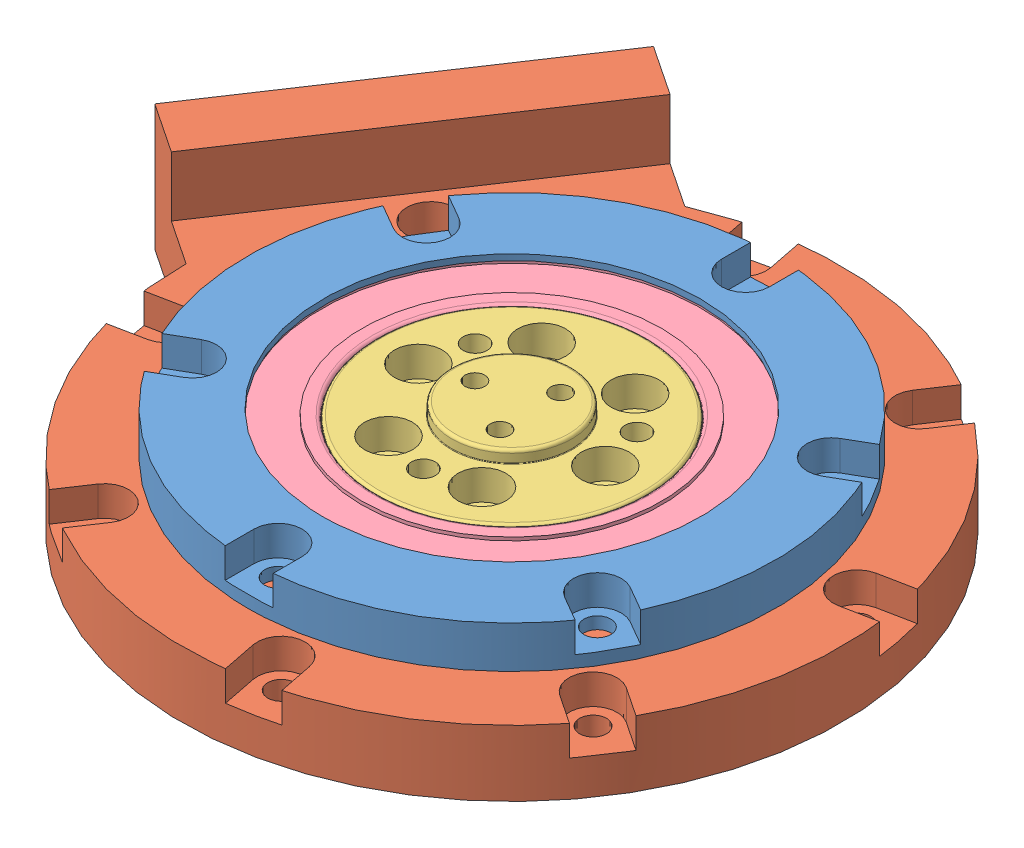
SolidWorks assembly Knee Assemble v2, configuration 기본. Lengths in mm.
Overall size (160.88 21 158.11).
4 component instances, 4 part files, 13 mates.
Components (placement in the parent):
- Actuator Jig Bearing Cap v2-1: Actuator Jig Bearing Cap v2 [기본] at (-1.6384 1.051 88) size (88 7 88)
- Actuator Jig v2-1: Actuator Jig v2 [기본] at (-1.6384 -9.949 88) x (0.831699 0 0.555227) z (-0.555227 0 0.831699) size (120 21 110)
- Load Flange v2-1: Load Flange v2 [기본] at (-1.6384 -9.949 88) x (-0.027558 0 -0.99962) z (0.99962 0 -0.027558) size (50 19 50)
- C-SE6909ZZ.stp-1: C-SE6909ZZ.stp [기본] at (-1.6384 -4.949 88) x (0 1 0) z (-0.818577 0 0.574397) size (12 68 68)
Mates (geometry in assembly coordinates):
- 동심1: concentric aligned: circle of Actuator Jig Bearing Cap v2-1; circle of Actuator Jig v2-1
- 동심2: concentric anti-aligned: circle of Actuator Jig v2-1; circle of NSK_7909A5-1/7909A5 Outer ring-1
- 일치4: coincident anti-aligned: plane of Actuator Jig v2-1 through (-1.6384 3.551 88) normal (0 1 0); plane of NSK_7909A5-1/7909A5 Outer ring-1 through (15.4759 -4.949 61.2574) normal (0 -1 0)
- 일치6: coincident anti-aligned: plane of Actuator Jig Bearing Cap v2-1 through (-1.6384 7.051 88) normal (0 -1 0); plane of NSK_7909A5-1/7909A5 Outer ring-1 through (16.3653 7.051 59.8677) normal (0 1 0)
- 동심3: concentric anti-aligned: circle of Load Flange v2-1; circle of NSK_7909A5-1/7909A5 Inner ring-1
- 일치7: coincident anti-aligned: plane of Load Flange v2-1 through (-1.6384 3.551 88) normal (0 1 0); plane of NSK_7909A5-1/7909A5 Inner ring-1 through (10.8132 -4.949 68.5432) normal (0 -1 0)
- 동심4: concentric anti-aligned: circle of NSK_7909A5-1/7909A5 Inner ring-1; circle of Knee Link v2-1
- 동심7: concentric aligned: circle of Load Flange v2-1; circle of Knee Link v2-1
- 동심8: concentric aligned: circle of Actuator Jig Bearing Cap v2-1; circle of C-SE6909ZZ.stp-1
- 동심10: concentric aligned: circle of Load Flange v2-1; circle of C-SE6909ZZ.stp-1
- 일치11: coincident anti-aligned: plane of Load Flange v2-1 through (-1.6384 -107.4753 88) normal (0 1 0); plane of C-SE6909ZZ.stp-1 through (-15.9983 -107.4753 67.5356) normal (0 -1 0)
- 일치12: coincident anti-aligned: plane of Actuator Jig v2-1 through (-1.6384 -4.949 88) normal (0 1 0); plane of C-SE6909ZZ.stp-1 through (-20.8232 -4.949 60.6595) normal (0 -1 0)
- 일치13: coincident anti-aligned: plane of Actuator Jig Bearing Cap v2-1 through (-1.6384 7.051 88) normal (0 -1 0); plane of C-SE6909ZZ.stp-1 through (-19.8755 7.051 62.0102) normal (0 1 0)
